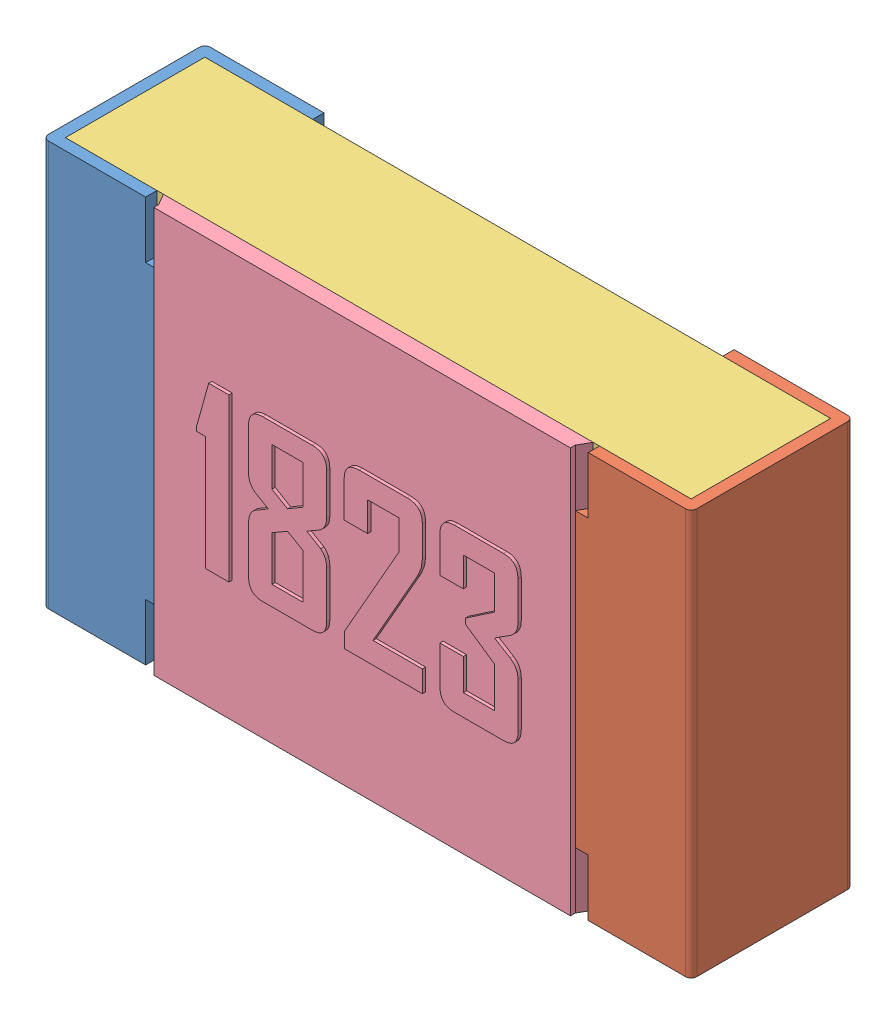
SolidWorks assembly RES_10K_0805, configuration Default. Lengths in mm.
Overall size (2 1.25 0.53).
4 component instances, 4 part files, 0 mates.
Components (placement in the parent):
- Pin1Body-1-1: Pin1Body-1 [Default] at (0 0 0.01) size (0.37 1.25 0.5)
- Pin2Body-1-1: Pin2Body-1 [Default] at (0 0 0.01) size (0.37 1.25 0.5)
- CeramicBody-1-1: CeramicBody-1 [Default] at (0 0 0.01) size (1.93 1.25 0.43)
- CoatingBody-1-1: CoatingBody-1 [Default] at (0 0 0.01) size (1.33 1.25 0.06)
